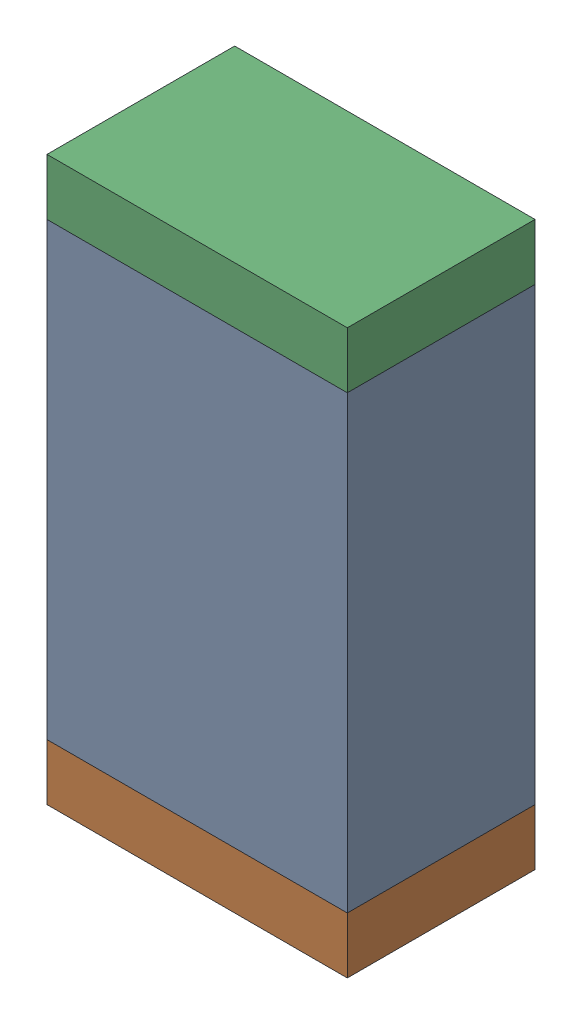
SolidWorks assembly R42, configuration Default. Lengths in mm.
Overall size (0.8 1.5 0.5).
6 component instances, 2 part files, 0 mates.
Components (placement in the parent):
- 810156976-1: 810156976 [Default] at (117.15 53.4 0) size (0.8 1.2 0.5)
  - Extruded_6-1: Extruded_6 [Default] at origin size (0.8 1.2 0.5)
- 810156592-1: 810156592 [Default] at (117.15 52.725 0) size (0.8 0.15 0.5)
  - Extruded_7-1: Extruded_7 [Default] at origin size (0.8 0.15 0.5)
- 810156592-2: 810156592 [Default] at (117.15 54.075 0) size (0.8 0.15 0.5)
  - Extruded_7-1: Extruded_7 [Default] at origin size (0.8 0.15 0.5)
